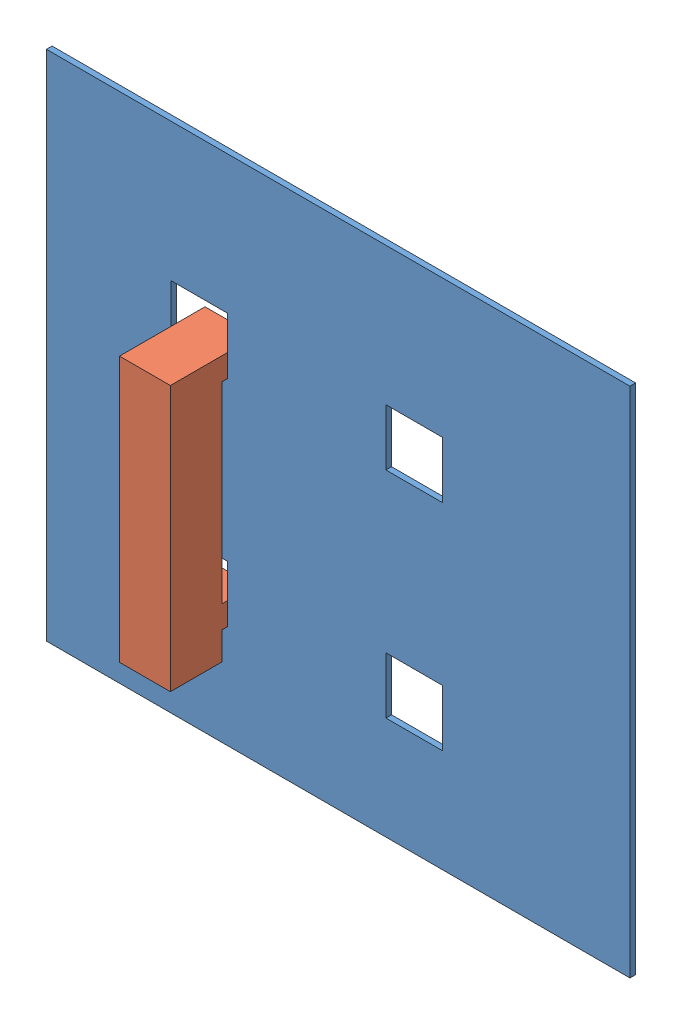
SolidWorks assembly Assemblage1, configuration Défaut. Lengths in mm.
Overall size (103.21 90.66 15.12).
2 component instances, 2 part files, 5 mates.
Components (placement in the parent):
- tableauperceFablab-1: tableauperceFablab [Défaut] at origin size (103.21 90.66 1)
- accroche-1: accroche [Défaut] at (10 -5 0.5) x (0 0 1) z (-1 0 0) size (15.12 47 9)
Mates (geometry in assembly coordinates):
- Parallèle1: parallel aligned: plane of tableauperceFablab-1 through (0 0 1) normal (0 0 1); plane of accroche-1 through (1 -4.9036 11.1219) normal (0 0 1)
- Parallèle2: parallel aligned: plane of tableauperceFablab-1 through (-22.049 72.418 1) normal (0 1 0); plane of accroche-1 through (1 42 11.1219) normal (0 1 0)
- Parallèle3: parallel aligned: plane of tableauperceFablab-1 through (81.1644 72.418 1) normal (1 0 0); plane of accroche-1 through (10 -5 0.5) normal (1 0 0)
- Coïncidente4: coincident anti-aligned: line of tableauperceFablab-1 through (10 38 1) axis (0 0 -1); line of accroche-1 through (10 38 0) axis (0 0 1)
- Coïncidente5: coincident aligned: line of tableauperceFablab-1 through (10 0 38) axis (0 1 0); line of accroche-1 through (1 38 0) axis (1 0 0)
